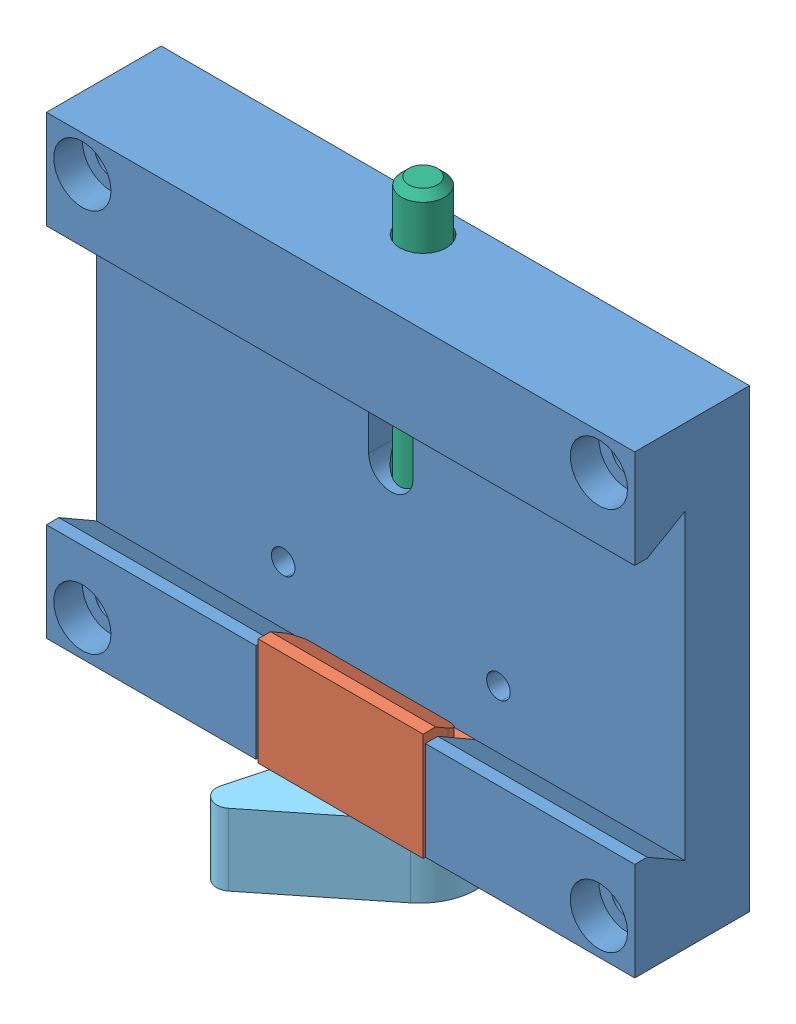
SolidWorks assembly qr_new_assembly, configuration По умолчанию. Lengths in mm.
Overall size (82 81.81 33.03).
8 component instances, 7 part files, 6 mates.
Components (placement in the parent):
- quick_plate_mod_1-1: quick_plate_mod_1 [широко] at (-110.1555 59.3768 33.5331) size (82 63.5 16)
- quick_plate_clip_mod_1-1: quick_plate_clip_mod_1 [По умолчанию] at (-57.6555 -4.4376 33.5331) x (0 -1 0) z (-1 0 0) size (15 16 43.2)
- flag_screw-1: flag_screw [По умолчанию] at (-96.6203 7.653 -7.7302) x (-0.837169 0 -0.546944) z (-0.546944 0 0.837169) size (16 29 29)
  - flag-1: flag [По умолчанию] at (-48.2962 13.0906 23.7085) size (16 10 29) (hidden)
  - socket head cap screw_din_1-1: socket head cap screw_din_1 [DIN 912 M4 x 25 --- 25N] at (-48.2962 23.0906 23.7085) x (0 -1 0) z (-0.387543 0 0.921852) size (29 7 7)
  - plain washer 6902 type abc_din-1: plain washer 6902 type abc_din [DIN 6902-A4.55] at (-48.2962 13.0906 23.7085) x (0 -1 0) z (-0.000413 0 1) size (1 10 10)
  - flag_drop-1: flag_drop [По умолчанию] at (-48.2962 13.0906 23.7085) x (1 0 0) z (0 1 0) size (16 29 10)
- knopka-1: knopka [По умолчанию] at (-69.1555 66.3688 38.0331) x (-0.106722 0 0.994289) z (0 -1 0) size (6 6 37)
Mates (geometry in assembly coordinates):
- Параллельность1: parallel anti-aligned: plane of quick_plate_mod_1-1 through (-80.9555 6.5468 7.6331) normal (0 -1 0); plane of quick_plate_clip_mod_1-1 through (-80.6555 5.637 44.0331) normal (0 1 0)
- Концентричный1: concentric aligned: cylinder of quick_plate_mod_1-1 through (-86.6555 6.4768 41.5331) axis (0 -1 0) radius 4.3; cylinder of quick_plate_clip_mod_1-1 through (-86.6555 18.6466 41.5331) axis (0 -1 0) radius 4.1
- Концентричный2: concentric aligned: cylinder of quick_plate_mod_1-1 through (-51.6555 6.4768 41.5331) axis (0 -1 0) radius 4.3; cylinder of quick_plate_clip_mod_1-1 through (-51.6555 18.6466 41.5331) axis (0 -1 0) radius 4.1
- Концентричный3: concentric aligned: cylinder of quick_plate_clip_mod_1-1 through (-69.1555 -4.4376 38.5331) axis (0 -1 0) radius 2.25; cylinder of flag_screw-1/socket head cap screw_din_1-1 through (-69.1555 -47.1876 38.5331) axis (0 -1 0) radius 2
- Совпадение2: coincident anti-aligned: plane of quick_plate_clip_mod_1-1 through (-80.6555 -4.4376 49.5331) normal (0 -1 0); plane of flag_screw-1/plain washer 6902 type abc_din-1 through (-69.1555 -4.4376 38.5331) normal (0 1 0)
- Концентричный4: concentric aligned: cylinder of quick_plate_mod_1-1 through (-69.1555 21.3768 38.0331) axis (0 1 0) radius 3.25; cylinder of knopka-1 through (-69.1555 29.3688 38.0331) axis (0 1 0) radius 3
